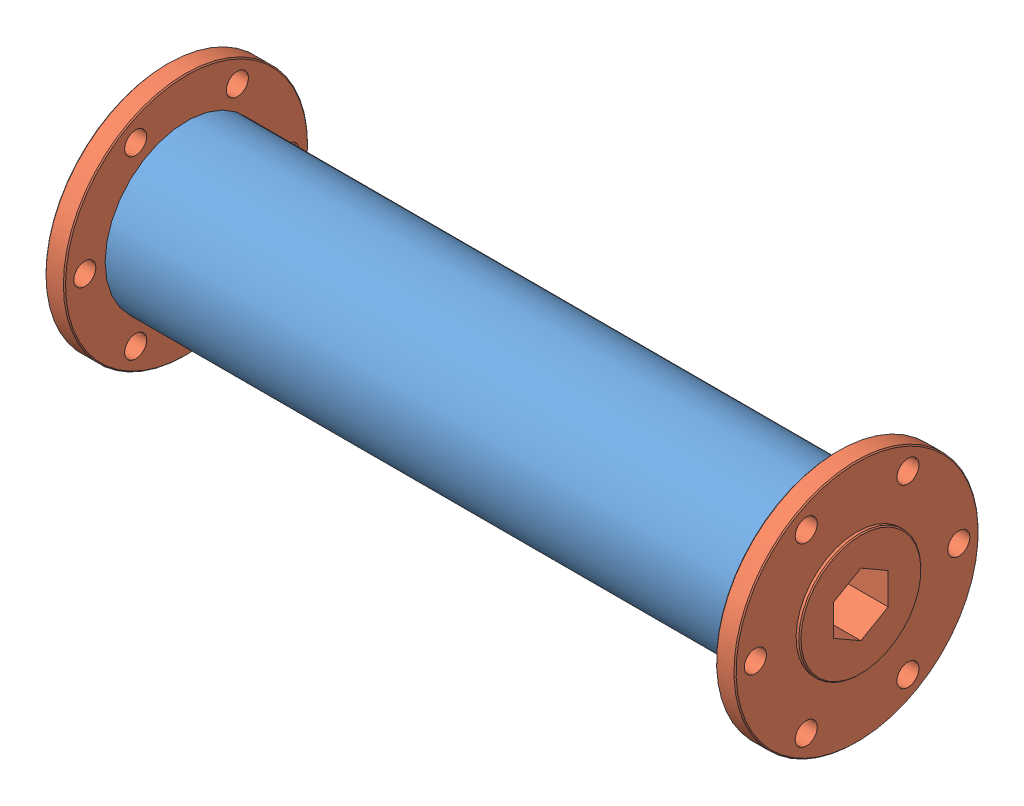
SolidWorks assembly 2018-319-A, configuration Default. Lengths in mm.
Overall size (163.32 78.07 78.07).
3 component instances, 2 part files, 5 mates.
Components (placement in the parent):
- 2018-319-D004-1: 2018-319-D004 [Default] at (-21.8207 -7.3506 16.5084) size (152.4 38.1 38.1)
- am-0096a+500+Hex+Hub+r2-1: am-0096a+500+Hex+Hub+r2 [Default] at (40.4553 -7.3506 16.5084) x (-1 0 0) z (0 -0.866025 -0.5) size (25.4 57.15 57.15)
- am-0096a+500+Hex+Hub+r2-2: am-0096a+500+Hex+Hub+r2 [Default] at (-84.0966 -7.3506 16.5084) size (25.4 57.15 57.15)
Mates (geometry in assembly coordinates):
- Concentric1: concentric anti-aligned: cylinder of 2018-319-D004-1 through (-167.2212 -7.3506 16.5084) axis (-1 0 0) radius 12.192; cylinder of am-0096a+500+Hex+Hub+r2-1 through (34.4403 -7.3506 16.5084) axis (1 0 0) radius 12.1666
- Coincident1: coincident anti-aligned: plane of 2018-319-D004-1 through (54.3793 11.6994 16.5084) normal (1 0 0); plane of am-0096a+500+Hex+Hub+r2-1 through (54.3793 -12.3098 13.6452) normal (-1 0 0)
- Concentric2: concentric aligned: cylinder of 2018-319-D004-1 through (-167.2212 -7.3506 16.5084) axis (-1 0 0) radius 12.192; cylinder of am-0096a+500+Hex+Hub+r2-2 through (-78.0817 -7.3506 16.5084) axis (-1 0 0) radius 12.1666
- Coincident2: coincident anti-aligned: plane of 2018-319-D004-1 through (-98.0207 11.6994 16.5084) normal (-1 0 0); plane of am-0096a+500+Hex+Hub+r2-2 through (-98.0207 -7.3506 22.2348) normal (1 0 0)
- Parallel1: parallel aligned: plane of am-0096a+500+Hex+Hub+r2-1 through (59.8403 -3.6698 22.8838) normal (0 -0.866025 -0.5); plane of am-0096a+500+Hex+Hub+r2-2 through (-103.4817 0.011 16.5084) normal (0 -0.866025 -0.5)
